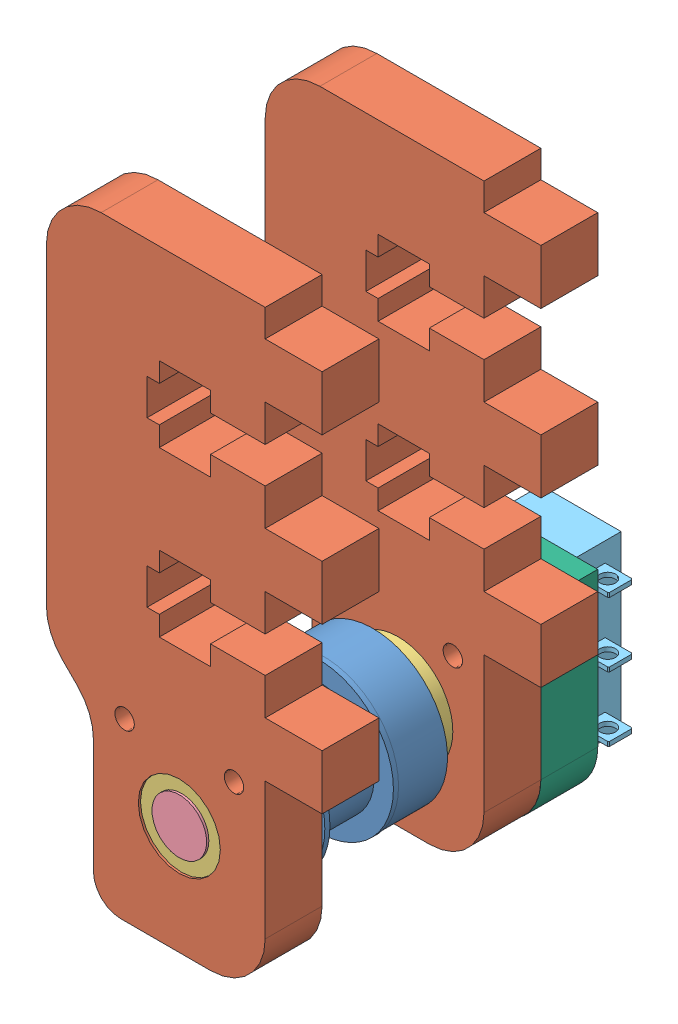
SolidWorks assembly PULLEY BLOCK, OUTFEED, configuration Default. Lengths in mm.
Overall size (32 69.85 45.11).
8 component instances, 6 part files, 19 mates.
Components (placement in the parent):
- 1375K39-1: 1375K39 [Default] at (-9.9695 -57.15 17.2085) x (1 0 0) z (0 1 0) size (17.4 14.3 17.4)
- MOUNT, PULLY-1: MOUNT, PULLY [Default] x (1 0 0) z (0 0 -1) size (32 69.85 6.6)
- MOUNT, PULLY-2: MOUNT, PULLY [Default] at (0 0 25.4) x (1 0 0) z (0 0 -1) size (32 69.85 6.6)
- 6338K411-1: 6338K411 [Default] at (-9.9695 -57.15 -6.35) x (-0.837169 -0.546944 0) z (-0.546944 0.837169 0) size (12.7 7.94 12.7)
- 6338K411-2: 6338K411 [Default] at (-9.9695 -57.15 25.146) x (0.871903 0.489679 0) z (-0.489679 0.871903 0) size (12.7 7.94 12.7)
- SHAFT, PULLY-1: SHAFT, PULLY [Default] at (-9.9695 -57.15 25.4) x (0.857168 -0.515036 0) z (0 0 -1) size (6.35 6.35 31.75)
- 7658K160-1: 7658K160 [Default] at (-3.7956 -56.9857 -16.4592) x (-0.000359 -1 0) z (0 0 -1) size (21.02 24.56 6.5)
- LIMIT SWITCH MOUNT, OUTFEED-1: LIMIT SWITCH MOUNT, OUTFEED [Default] at (-9.9695 -45.6438 -6.604) x (1 0 0) z (0 1 0) size (19.94 6.6 24.21)
Mates (geometry in assembly coordinates):
- Concentric1: concentric anti-aligned: cylinder of 1375K39-1 through (-9.9695 -57.15 -9.4741) axis (0 0 -1) radius 3.175; cylinder of MOUNT, PULLY-1 through (-9.9695 -57.15 -6.604) axis (0 0 1) radius 4.7625
- Concentric2: concentric aligned: cylinder of MOUNT, PULLY-1 through (-9.9695 -57.15 -6.604) axis (0 0 1) radius 4.7625; cylinder of MOUNT, PULLY-2 through (-9.9695 -57.15 18.796) axis (0 0 1) radius 4.7625
- Concentric3: concentric aligned: cylinder of MOUNT, PULLY-2 through (-9.9695 -57.15 18.796) axis (0 0 1) radius 4.7625; cylinder of 6338K411-2 through (-9.9695 -57.15 25.146) axis (0 0 1) radius 4.7625
- Concentric4: concentric anti-aligned: cylinder of MOUNT, PULLY-1 through (-9.9695 -57.15 -6.604) axis (0 0 1) radius 4.7625; cylinder of 6338K411-1 through (-9.9695 -57.15 -6.35) axis (0 0 -1) radius 4.7625
- Coincident3: coincident anti-aligned: plane of MOUNT, PULLY-1 through (0 0 0) normal (0 0 1); plane of 6338K411-1 through (-6.4964 -62.466 0) normal (0 0 -1)
- Coincident4: coincident aligned: plane of MOUNT, PULLY-1 through (-25.4 0 -6.604) normal (-1 0 0); plane of MOUNT, PULLY-2 through (-25.4 0 18.796) normal (-1 0 0)
- Coincident5: coincident anti-aligned: plane of MOUNT, PULLY-2 through (0 0 18.796) normal (0 0 -1); plane of 6338K411-2 through (-6.86 -62.6866 18.796) normal (0 0 1)
- Distance1: distance = 25.4 mm aligned: plane of MOUNT, PULLY-1 through (0 0 -6.604) normal (0 0 -1); plane of MOUNT, PULLY-2 through (0 0 18.796) normal (0 0 -1)
- Coincident7: coincident anti-aligned: plane of 1375K39-1 through (-6.7945 -57.15 17.2085) normal (0 0 1); plane of 6338K411-2 through (-8.4148 -59.9183 17.2085) normal (0 0 -1)
- Concentric5: concentric anti-aligned: cylinder of 6338K411-1 through (-9.9695 -57.15 -6.35) axis (0 0 -1) radius 3.175; cylinder of SHAFT, PULLY-1 through (-9.9695 -57.15 -6.35) axis (0 0 1) radius 3.175
- Coincident8: coincident aligned: plane of MOUNT, PULLY-2 through (0 0 25.4) normal (0 0 1); plane of SHAFT, PULLY-1 through (-9.9695 -57.15 25.4) normal (0 0 1)
- Coincident11: coincident anti-aligned: plane of MOUNT, PULLY-1 through (0 0 0) normal (0 0 -1); plane of assembly through (0 0 0) normal (0 0 1)
- Coincident12: coincident anti-aligned: plane of MOUNT, PULLY-1 through (0 0 0) normal (0 -1 0); plane of assembly through (0 0 0) normal (0 1 0)
- Coincident13: coincident aligned: plane of MOUNT, PULLY-1; plane of assembly through (0 0 0) normal (1 0 0)
- Coincident15: coincident anti-aligned: plane of MOUNT, PULLY-1 through (0 0 -6.604) normal (0 0 -1); plane of LIMIT SWITCH MOUNT, OUTFEED-1 through (-9.9695 -45.6438 -6.604) normal (0 0 1)
- Coincident16: coincident anti-aligned: plane of 7658K160-1 through (-3.7992 -66.9806 -13.208) normal (0 0 1); plane of LIMIT SWITCH MOUNT, OUTFEED-1 through (-9.9695 -45.6438 -13.208) normal (0 0 -1)
- Concentric6: concentric anti-aligned: cylinder of 7658K160-1 through (-6.1595 -61.7728 -19.7104) axis (0 0 1) radius 1.1049; cylinder of LIMIT SWITCH MOUNT, OUTFEED-1 through (-6.1595 -61.7728 -13.208) axis (0 0 -1) radius 1.1303
- Concentric7: concentric aligned: cylinder of MOUNT, PULLY-1 through (-3.6195 -49.53 -6.604) axis (0 0 -1) radius 1.1303; cylinder of LIMIT SWITCH MOUNT, OUTFEED-1 through (-3.6195 -49.53 -13.208) axis (0 0 -1) radius 1.632
- Concentric8: concentric aligned: cylinder of MOUNT, PULLY-1 through (-16.3195 -49.53 -6.604) axis (0 0 -1) radius 1.1303; cylinder of LIMIT SWITCH MOUNT, OUTFEED-1 through (-16.3195 -49.53 -13.208) axis (0 0 -1) radius 1.632
